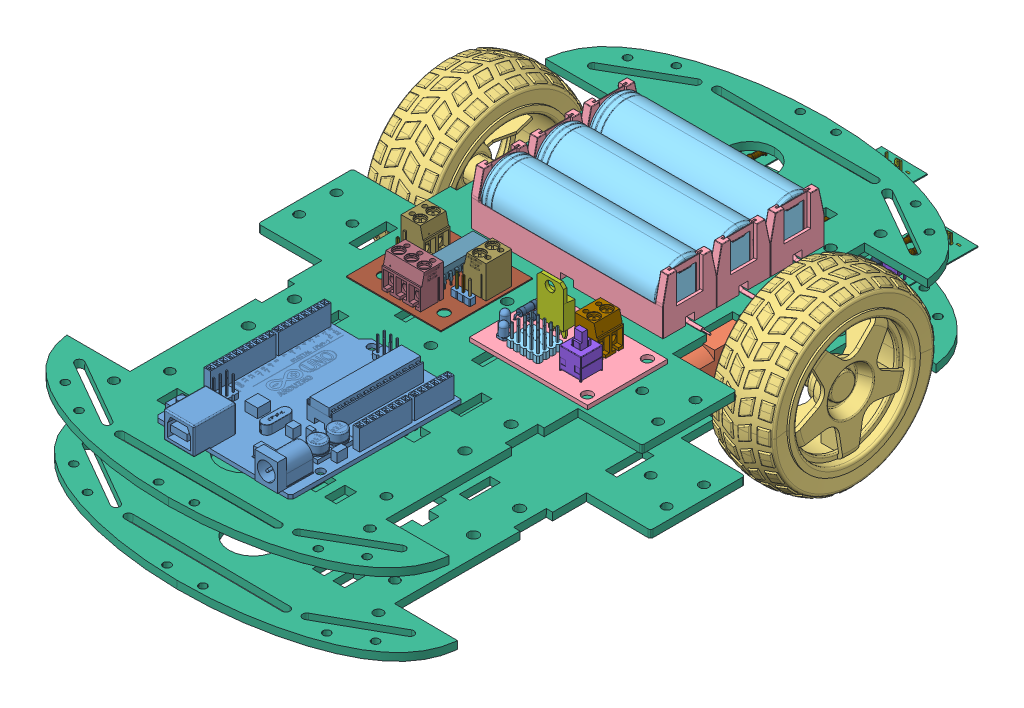
SolidWorks assembly Line Follower, configuration Default. Lengths in mm.
Overall size (160.4 73.81 283.83).
134 component instances, 42 part files, 13 mates.
Components (placement in the parent):
- Arduino-1: Arduino [Predeterminado] at (-169.344 67.8396 211.6674) x (0.008727 0 -0.999962) z (0.999962 0 0.008727) size (74.8 15.1 53.3)
- Motor and Wheel-3: Motor and Wheel [Default] at (-166.8076 90.6853 68.1678) x (1 0 0) z (0 0 -1) size (57.95 69.08 87.78)
  - Motor-1: Motor [Default] at (43.2822 36.5956 -6.1414) size (37.2 22.5 65.5)
  - Wheel-1: Wheel [Default] at (82.6322 37.3457 -18.4581) x (0 0 -1) z (1 0 0) size (69.1 69.08 30)
- Caster Ball Wheel.STEP-1: Caster Ball Wheel.STEP [Default] at (-164.1119 39.4018 172.6288) x (-0.999962 0.008727 0) z (0 0 1) size (47 18.41 32)
  - Wheel''s Body.STEP-1: Wheel''s Body.STEP [Default] at origin size (47 8.6 32)
  - Ball.STEP-1: Ball.STEP [Default] at (0 8.6 0) x (0.870425 -0.365315 -0.330008) z (0.347375 -0.019238 0.937529) size (14 14 14)
- IR Sensor.step-1: IR Sensor.step [Default] at (-98.685 42.2424 150.0634) x (0.008726 -0.000076 -0.999962) z (0.008727 0.999962 0) size (50.17 18.03 34.75)
  - Board.step-1: Board.step [Default] at origin size (50.17 18.03 0.41)
    - Open CASCADE STEP translator 6.8 1.1.1.step-1: Open CASCADE STEP translator 6.8 1.1.1.step [Default] at (0 0 -0.4115) size (50.17 18.03 0.41)
  - TCRT5000.step-1: TCRT5000.step [Default] at origin size (6.8 10.2 11)
    - TCRT5000-0.step-1: TCRT5000-0.step [Default] at (156.0539 65.342 0.0711) x (0 1 0) z (-1 0 0) size (10.2 11 6.8)
  - R4.step-1: R4.step [Default] at origin size (6.55 6.79 6.95)
    - CA6XV5-5KA2020SNP.step-1: CA6XV5-5KA2020SNP.step [Default] at (136.425 60.4731 2.2572) x (-1 0 0) z (0 0 1) size (6.55 6.79 6.95)
  - LM358P.step-1: LM358P.step [Default] at origin size (10.92 9.59 8.26)
    - LM358.step-1: LM358.step [Default] at (125.8569 64.1349 2) x (0 1 0) z (1 0 0) size (9.59 8.26 10.92)
  - LED1.step-1: LED1.step [Default] at origin size (3.57 3.9 31.7)
    - 154003xxx.step-1: 154003xxx.step [Default] at (136.5249 71.3739 0.03) x (-1 0 0) z (0 0 1) size (3.57 3.9 31.7)
  - Free-Models.step-1: Free-Models.step [Default] at origin size (28.98 13.71 11.68)
    - 1x3_TH_Vert_100mil.step-1: 1x3_TH_Vert_100mil.step [Default] at (128.397 72.263 0) x (-1 0 0) z (0 0 1) size (0.64 0.64 3.3)
    - 1x3_TH_Vert_100mil-1.step-1: 1x3_TH_Vert_100mil-1.step [Default] at (128.397 72.263 0) x (-1 0 0) z (0 0 1) size (0.64 0.64 8.38)
    - 1x3_TH_Vert_100mil-2.step-1: 1x3_TH_Vert_100mil-2.step [Default] at (128.397 72.263 0) x (-1 0 0) z (0 0 1) size (0.64 0.64 3.3)
    - 1x3_TH_Vert_100mil-3.step-1: 1x3_TH_Vert_100mil-3.step [Default] at (128.397 72.263 0) x (-1 0 0) z (0 0 1) size (0.64 0.64 8.38)
    - 1x3_TH_Vert_100mil-4.step-1: 1x3_TH_Vert_100mil-4.step [Default] at (128.397 72.263 0) x (-1 0 0) z (0 0 1) size (7.62 2.54 2.5)
    - 1x3_TH_Vert_100mil-5.step-1: 1x3_TH_Vert_100mil-5.step [Default] at (128.397 72.263 0) x (-1 0 0) z (0 0 1) size (0.64 0.64 3.3)
    - 1x3_TH_Vert_100mil-6.step-1: 1x3_TH_Vert_100mil-6.step [Default] at (128.397 72.263 0) x (-1 0 0) z (0 0 1) size (0.64 0.64 8.38)
    - Resistor_10K_Ohm_tol1pct_0,25W__07,62.step-1: Resistor_10K_Ohm_tol1pct_0,25W__07,62.step [Default] at (146.939 71.374 2) x (0 1 0) z (0 0 1) size (2.35 8.17 5.67)
    - Resistor_10K_Ohm_tol1pct_0,25W__07,62.step-2: Resistor_10K_Ohm_tol1pct_0,25W__07,62.step [Default] at (146.939 61 2) x (0 1 0) z (0 0 1) size (2.35 8.17 5.67)
    - Resistor_10K_Ohm_tol1pct_0,25W__07,62.step-3: Resistor_10K_Ohm_tol1pct_0,25W__07,62.step [Default] at (146.939 66.187 2) x (0 -1 0) z (0 0 1) size (2.35 8.17 5.67)
- Power Distribution.step-1: Power Distribution.step [Default] at (-125.3146 67.8396 131.7909) x (-1 0 0) z (0 1 0) size (46.1 31.17 28.88)
  - PCB Component.step-1: PCB Component.step [Default] at origin size (46.1 31.17 28.88)
    - LED3MM.step-1: LED3MM.step [Default] at (30.48 20.32 1.57) x (0 1 0) z (0 0 1) size (3.45 3.85 8.38)
      - LEDBody.step-1: LEDBody.step [Default] at (0 0 0.01) size (3.45 3.85 5.38)
      - Lead1Body.step-1: Lead1Body.step [Default] at (0 0 0.01) size (0.5 0.5 3)
      - Lead2Body.step-1: Lead2Body.step [Default] at (0 0 0.01) size (0.5 0.5 3)
    - LED3MM.step-2: LED3MM.step [Default] at (34.29 16.002 1.57) x (0 1 0) z (0 0 1) size (3.45 3.85 8.38)
      - LEDBody.step-1: LEDBody.step [Default] at (0 0 0.01) size (3.45 3.85 5.38)
      - Lead1Body.step-1: Lead1Body.step [Default] at (0 0 0.01) size (0.5 0.5 3)
      - Lead2Body.step-1: Lead2Body.step [Default] at (0 0 0.01) size (0.5 0.5 3)
    - Board.step-1: Board.step [Default] at origin size (46.1 31.17 1.57)
    - 2X05.step-1: 2X05.step [Default] at (20.828 20.32 1.57) size (12.7 5.08 11.34)
    - 2X05.step-2: 2X05.step [Default] at (20.828 15.24 1.57) x (-1 0 0) z (0 0 1) size (12.7 5.08 11.34)
    - 1N4004.step-1: 1N4004.step [Default] at (20.853 1.118 1.57) x (-1 0 0) z (0 0 1) size (10.6 2.5 4.42)
    - 7805.step-1: 7805.step [Default] at (20.853 11.125 1.57) size (10.39 4.6 28.88)
    - PVA2R.step-1: PVA2R.step [Default] at (4.14 16.459 1.57) size (8.5 8.5 17)
    - AK500_2-H.step-1: AK500_2-H.step [Default] at (7.366 5.588 1.57) x (0 -1 0) z (0 0 1) size (10.6 9 17)
    - 220.step-1: 220.step [Default] at (30.48 7.112 1.57) x (0 -1 0) z (0 0 1) size (10.6 2.5 4.42)
    - 220.step-2: 220.step [Default] at (34.29 7.112 1.57) x (0 -1 0) z (0 0 1) size (10.6 2.5 4.42)
- L293D.STEP-1: L293D.STEP [Default] at (-84.8079 68.2511 189.7872) x (0 0 -1) z (0 1 0) size (35.69 36.96 17)
  - Board.step.STEP-1: Board.step.STEP [Default] at origin size (35.69 36.96 0.41)
    - Open CASCADE STEP translator 6.8 2.1.1.step.STEP-1: Open CASCADE STEP translator 6.8 2.1.1.step.STEP [Default] at (0 0 -0.4115) size (35.69 36.96 0.41)
  - MOTOR2-OUT.step.STEP-1: MOTOR2-OUT.step.STEP [Default] at origin size (10.6 9 17)
    - DG300-5.0-02P-12-00AH.step.STEP-1: DG300-5.0-02P-12-00AH.step.STEP [Default] at (47.6021 120.9511 0) x (1 0 0) z (0 -1 0) size (10.6 17 9)
  - POWER.step.STEP-1: POWER.step.STEP [Default] at origin size (9 15.6 17)
    - DG300-5.0-03P-12-00AH.step.STEP-1: DG300-5.0-03P-12-00AH.step.STEP [Default] at (40.0521 111.8229 0) x (0 -1 0) z (-1 0 0) size (15.6 17 9)
  - MOTOR1-OUT.step.STEP-1: MOTOR1-OUT.step.STEP [Default] at origin size (10.6 9 17)
    - DG300-5.0-02P-12-00AH.step.STEP-1: DG300-5.0-02P-12-00AH.step.STEP [Default] at (57.5539 87.7099 0) x (-1 0 0) z (0 1 0) size (10.6 17 9)
  - L1.step.STEP-1: L1.step.STEP [Default] at origin size (20 9.24 8.4)
    - L293D.step.STEP-1: L293D.step.STEP [Default] at (52.5271 104.2671 1.27) x (1 0 0) z (0 -1 0) size (20 8.4 9.24)
  - Free-Models.step.STEP-1: Free-Models.step.STEP [Default] at origin size (2.54 30.74 11.68)
    - 1x3_TH_Vert_100mil.step.STEP-1: 1x3_TH_Vert_100mil.step.STEP [Default] at (43.688 90.17 0) x (0 1 0) z (0 0 1) size (0.64 0.64 3.3)
    - 1x3_TH_Vert_100mil-0.step.STEP-1: 1x3_TH_Vert_100mil-0.step.STEP [Default] at (43.688 90.17 0) x (0 1 0) z (0 0 1) size (0.64 0.64 8.38)
    - 1x3_TH_Vert_100mil-1.step.STEP-1: 1x3_TH_Vert_100mil-1.step.STEP [Default] at (43.688 90.17 0) x (0 1 0) z (0 0 1) size (0.64 0.64 3.3)
    - 1x3_TH_Vert_100mil-2.step.STEP-1: 1x3_TH_Vert_100mil-2.step.STEP [Default] at (43.688 90.17 0) x (0 1 0) z (0 0 1) size (0.64 0.64 8.38)
    - 1x3_TH_Vert_100mil-3.step.STEP-1: 1x3_TH_Vert_100mil-3.step.STEP [Default] at (43.688 90.17 0) x (0 1 0) z (0 0 1) size (7.62 2.54 2.5)
    - 1x3_TH_Vert_100mil-4.step.STEP-1: 1x3_TH_Vert_100mil-4.step.STEP [Default] at (43.688 90.17 0) x (0 1 0) z (0 0 1) size (0.64 0.64 3.3)
    - 1x3_TH_Vert_100mil-5.step.STEP-1: 1x3_TH_Vert_100mil-5.step.STEP [Default] at (43.688 90.17 0) x (0 1 0) z (0 0 1) size (0.64 0.64 8.38)
    - 1x3_TH_Vert_100mil.step.STEP-2: 1x3_TH_Vert_100mil.step.STEP [Default] at (43.688 113.286 0) x (0 1 0) z (0 0 1) size (0.64 0.64 3.3)
    - 1x3_TH_Vert_100mil-0.step.STEP-2: 1x3_TH_Vert_100mil-0.step.STEP [Default] at (43.688 113.286 0) x (0 1 0) z (0 0 1) size (0.64 0.64 8.38)
    - 1x3_TH_Vert_100mil-1.step.STEP-2: 1x3_TH_Vert_100mil-1.step.STEP [Default] at (43.688 113.286 0) x (0 1 0) z (0 0 1) size (0.64 0.64 3.3)
    - 1x3_TH_Vert_100mil-2.step.STEP-2: 1x3_TH_Vert_100mil-2.step.STEP [Default] at (43.688 113.286 0) x (0 1 0) z (0 0 1) size (0.64 0.64 8.38)
    - 1x3_TH_Vert_100mil-3.step.STEP-2: 1x3_TH_Vert_100mil-3.step.STEP [Default] at (43.688 113.286 0) x (0 1 0) z (0 0 1) size (7.62 2.54 2.5)
    - 1x3_TH_Vert_100mil-4.step.STEP-2: 1x3_TH_Vert_100mil-4.step.STEP [Default] at (43.688 113.286 0) x (0 1 0) z (0 0 1) size (0.64 0.64 3.3)
    - 1x3_TH_Vert_100mil-5.step.STEP-2: 1x3_TH_Vert_100mil-5.step.STEP [Default] at (43.688 113.286 0) x (0 1 0) z (0 0 1) size (0.64 0.64 8.38)
- Motor and Wheel-4: Motor and Wheel [Default] at (-161.9627 17.0365 68.1678) x (-0.999962 0.008727 0) z (0 0 -1) size (57.95 69.08 87.78)
  - Motor-1: Motor [Default] at (43.2822 36.5956 -6.1414) size (37.2 22.5 65.5)
  - Wheel-1: Wheel [Default] at (82.6322 37.3457 -18.4581) x (0 0 -1) z (1 0 0) size (69.1 69.08 30)
- IR Sensor.step-2: IR Sensor.step [Default] at (-64.5985 41.9449 164.3348) x (0.008726 -0.000076 -0.999962) z (0.008727 0.999962 0) size (50.17 18.03 34.75)
  - Board.step-1: Board.step [Default] at origin size (50.17 18.03 0.41)
    - Open CASCADE STEP translator 6.8 1.1.1.step-1: Open CASCADE STEP translator 6.8 1.1.1.step [Default] at (0 0 -0.4115) size (50.17 18.03 0.41)
  - TCRT5000.step-1: TCRT5000.step [Default] at origin size (6.8 10.2 11)
    - TCRT5000-0.step-1: TCRT5000-0.step [Default] at (156.0539 65.342 0.0711) x (0 1 0) z (-1 0 0) size (10.2 11 6.8)
  - R4.step-1: R4.step [Default] at origin size (6.55 6.79 6.95)
    - CA6XV5-5KA2020SNP.step-1: CA6XV5-5KA2020SNP.step [Default] at (136.425 60.4731 2.2572) x (-1 0 0) z (0 0 1) size (6.55 6.79 6.95)
  - LM358P.step-1: LM358P.step [Default] at origin size (10.92 9.59 8.26)
    - LM358.step-1: LM358.step [Default] at (125.8569 64.1349 2) x (0 1 0) z (1 0 0) size (9.59 8.26 10.92)
  - LED1.step-1: LED1.step [Default] at origin size (3.57 3.9 31.7)
    - 154003xxx.step-1: 154003xxx.step [Default] at (136.5249 71.3739 0.03) x (-1 0 0) z (0 0 1) size (3.57 3.9 31.7)
  - Free-Models.step-1: Free-Models.step [Default] at origin size (28.98 13.71 11.68)
    - 1x3_TH_Vert_100mil.step-1: 1x3_TH_Vert_100mil.step [Default] at (128.397 72.263 0) x (-1 0 0) z (0 0 1) size (0.64 0.64 3.3)
    - 1x3_TH_Vert_100mil-1.step-1: 1x3_TH_Vert_100mil-1.step [Default] at (128.397 72.263 0) x (-1 0 0) z (0 0 1) size (0.64 0.64 8.38)
    - 1x3_TH_Vert_100mil-2.step-1: 1x3_TH_Vert_100mil-2.step [Default] at (128.397 72.263 0) x (-1 0 0) z (0 0 1) size (0.64 0.64 3.3)
    - 1x3_TH_Vert_100mil-3.step-1: 1x3_TH_Vert_100mil-3.step [Default] at (128.397 72.263 0) x (-1 0 0) z (0 0 1) size (0.64 0.64 8.38)
    - 1x3_TH_Vert_100mil-4.step-1: 1x3_TH_Vert_100mil-4.step [Default] at (128.397 72.263 0) x (-1 0 0) z (0 0 1) size (7.62 2.54 2.5)
    - 1x3_TH_Vert_100mil-5.step-1: 1x3_TH_Vert_100mil-5.step [Default] at (128.397 72.263 0) x (-1 0 0) z (0 0 1) size (0.64 0.64 3.3)
    - 1x3_TH_Vert_100mil-6.step-1: 1x3_TH_Vert_100mil-6.step [Default] at (128.397 72.263 0) x (-1 0 0) z (0 0 1) size (0.64 0.64 8.38)
    - Resistor_10K_Ohm_tol1pct_0,25W__07,62.step-1: Resistor_10K_Ohm_tol1pct_0,25W__07,62.step [Default] at (146.939 71.374 2) x (0 1 0) z (0 0 1) size (2.35 8.17 5.67)
    - Resistor_10K_Ohm_tol1pct_0,25W__07,62.step-2: Resistor_10K_Ohm_tol1pct_0,25W__07,62.step [Default] at (146.939 61 2) x (0 1 0) z (0 0 1) size (2.35 8.17 5.67)
    - Resistor_10K_Ohm_tol1pct_0,25W__07,62.step-3: Resistor_10K_Ohm_tol1pct_0,25W__07,62.step [Default] at (146.939 66.187 2) x (0 -1 0) z (0 0 1) size (2.35 8.17 5.67)
- IR Sensor.step-3: IR Sensor.step [Default] at (-132.7531 42.5397 164.3348) x (0.008726 -0.000076 -0.999962) z (0.008727 0.999962 0) size (50.17 18.03 34.75)
  - Board.step-1: Board.step [Default] at origin size (50.17 18.03 0.41)
    - Open CASCADE STEP translator 6.8 1.1.1.step-1: Open CASCADE STEP translator 6.8 1.1.1.step [Default] at (0 0 -0.4115) size (50.17 18.03 0.41)
  - TCRT5000.step-1: TCRT5000.step [Default] at origin size (6.8 10.2 11)
    - TCRT5000-0.step-1: TCRT5000-0.step [Default] at (156.0539 65.342 0.0711) x (0 1 0) z (-1 0 0) size (10.2 11 6.8)
  - R4.step-1: R4.step [Default] at origin size (6.55 6.79 6.95)
    - CA6XV5-5KA2020SNP.step-1: CA6XV5-5KA2020SNP.step [Default] at (136.425 60.4731 2.2572) x (-1 0 0) z (0 0 1) size (6.55 6.79 6.95)
  - LM358P.step-1: LM358P.step [Default] at origin size (10.92 9.59 8.26)
    - LM358.step-1: LM358.step [Default] at (125.8569 64.1349 2) x (0 1 0) z (1 0 0) size (9.59 8.26 10.92)
  - LED1.step-1: LED1.step [Default] at origin size (3.57 3.9 31.7)
    - 154003xxx.step-1: 154003xxx.step [Default] at (136.5249 71.3739 0.03) x (-1 0 0) z (0 0 1) size (3.57 3.9 31.7)
  - Free-Models.step-1: Free-Models.step [Default] at origin size (28.98 13.71 11.68)
    - 1x3_TH_Vert_100mil.step-1: 1x3_TH_Vert_100mil.step [Default] at (128.397 72.263 0) x (-1 0 0) z (0 0 1) size (0.64 0.64 3.3)
    - 1x3_TH_Vert_100mil-1.step-1: 1x3_TH_Vert_100mil-1.step [Default] at (128.397 72.263 0) x (-1 0 0) z (0 0 1) size (0.64 0.64 8.38)
    - 1x3_TH_Vert_100mil-2.step-1: 1x3_TH_Vert_100mil-2.step [Default] at (128.397 72.263 0) x (-1 0 0) z (0 0 1) size (0.64 0.64 3.3)
    - 1x3_TH_Vert_100mil-3.step-1: 1x3_TH_Vert_100mil-3.step [Default] at (128.397 72.263 0) x (-1 0 0) z (0 0 1) size (0.64 0.64 8.38)
    - 1x3_TH_Vert_100mil-4.step-1: 1x3_TH_Vert_100mil-4.step [Default] at (128.397 72.263 0) x (-1 0 0) z (0 0 1) size (7.62 2.54 2.5)
    - 1x3_TH_Vert_100mil-5.step-1: 1x3_TH_Vert_100mil-5.step [Default] at (128.397 72.263 0) x (-1 0 0) z (0 0 1) size (0.64 0.64 3.3)
    - 1x3_TH_Vert_100mil-6.step-1: 1x3_TH_Vert_100mil-6.step [Default] at (128.397 72.263 0) x (-1 0 0) z (0 0 1) size (0.64 0.64 8.38)
    - Resistor_10K_Ohm_tol1pct_0,25W__07,62.step-1: Resistor_10K_Ohm_tol1pct_0,25W__07,62.step [Default] at (146.939 71.374 2) x (0 1 0) z (0 0 1) size (2.35 8.17 5.67)
    - Resistor_10K_Ohm_tol1pct_0,25W__07,62.step-2: Resistor_10K_Ohm_tol1pct_0,25W__07,62.step [Default] at (146.939 61 2) x (0 1 0) z (0 0 1) size (2.35 8.17 5.67)
    - Resistor_10K_Ohm_tol1pct_0,25W__07,62.step-3: Resistor_10K_Ohm_tol1pct_0,25W__07,62.step [Default] at (146.939 66.187 2) x (0 -1 0) z (0 0 1) size (2.35 8.17 5.67)
- Power-1: Power [Default] at (-170.9418 66.3043 57.265) x (0 0 -1) z (0 1 0) size (21.01 91 23.5)
  - Battery Holder.stp-1: Battery Holder.stp [Default] at (-10.3221 -7.8579 1.0354) size (21.01 91 22.5)
  - Battery-1: Battery [Default] at (-10.3221 -43.3579 12.5354) size (21 70.03 21)
- Power-2: Power [Default] at (-170.9418 66.3043 78.265) x (0 0 -1) z (0 1 0) size (21.01 91 23.5)
  - Battery Holder.stp-1: Battery Holder.stp [Default] at (-10.3221 -7.8579 1.0354) size (21.01 91 22.5)
  - Battery-1: Battery [Default] at (-10.3221 -43.3579 12.5354) size (21 70.03 21)
- Power-3: Power [Default] at (-170.9418 66.3043 99.265) x (0 0 -1) z (0 1 0) size (21.01 91 23.5)
  - Battery Holder.stp-1: Battery Holder.stp [Default] at (-10.3221 -7.8579 1.0354) size (21.01 91 22.5)
  - Battery-1: Battery [Default] at (-10.3221 -43.3579 12.5354) size (21 70.03 21)
- 4WD Chassis.STEP-1: 4WD Chassis.STEP [Default] at (22.7736 40.771 142.6885) x (0.999962 -0.008727 0) z (-0.008727 -0.999962 0) size (150 257 3)
  - buggy chassis orig v3.stp.STEP-1: buggy chassis orig v3.stp.STEP [Default] at origin size (150 257 3)
- 4WD Chassis.STEP-2: 4WD Chassis.STEP [Default] at (18.4703 67.8396 141.7068) x (1 0 0) z (0 -1 0) size (150 257 3)
  - buggy chassis orig v3.stp.STEP-1: buggy chassis orig v3.stp.STEP [Default] at origin size (150 257 3)
Mates (geometry in assembly coordinates):
- Parallel3: parallel aligned: plane of Motor and Wheel-3/Motor-1 through (-123.5254 54.0896 74.3092) normal (0 0 -1); plane of Motor and Wheel-4/Motor-1 through (-204.9239 54.0085 74.3092) normal (0 0 -1)
- Coincident22: coincident anti-aligned: plane of Power-1/Battery Holder.stp-1 through (-163.0838 67.3396 78.087) normal (0 0 1); plane of Power-2/Battery Holder.stp-1 through (-163.0838 67.3396 78.087) normal (0 0 -1)
- Coincident24: coincident aligned: plane of Power-1/Battery Holder.stp-1 through (-200.5838 67.3396 67.587) normal (-1 0 0); plane of Power-2/Battery Holder.stp-1 through (-200.5838 67.3396 88.587) normal (-1 0 0)
- Coincident25: coincident anti-aligned: plane of Power-2/Battery Holder.stp-1 through (-163.0838 67.3396 99.087) normal (0 0 1); plane of Power-3/Battery Holder.stp-1 through (-163.0838 67.3396 99.087) normal (0 0 -1)
- Coincident26: coincident aligned: plane of Power-2/Battery Holder.stp-1 through (-125.5838 67.3396 88.587) normal (1 0 0); plane of Power-3/Battery Holder.stp-1 through (-125.5838 67.3396 109.587) normal (1 0 0)
- Coincident27: coincident anti-aligned: plane of Motor and Wheel-4/Motor-1 through (-214.3718 42.8405 74.3092) normal (-0.008727 -0.999962 0); plane of 4WD Chassis.STEP-1/buggy chassis orig v3.stp.STEP-1 through (-201.8722 42.7314 206.9385) normal (0.008727 0.999962 0)
- Coincident31: coincident anti-aligned: line of Motor and Wheel-4/Motor-1 through (-214.3718 42.8405 77.7092) axis (0 0 1); line of 4WD Chassis.STEP-1/buggy chassis orig v3.stp.STEP-1 through (-214.3718 42.8405 98.2416) axis (0 0 -1)
- Coincident34: coincident anti-aligned: plane of IR Sensor.step-2/Board.step-1/Open CASCADE STEP translator 6.8 1.1.1.step-1 through (-121.2794 42.0281 51.9489) normal (-0.008727 -0.999962 0); plane of 4WD Chassis.STEP-1/buggy chassis orig v3.stp.STEP-1 through (-201.8722 42.7314 206.9385) normal (0.008727 0.999962 0)
- Coincident35: coincident anti-aligned: plane of IR Sensor.step-1/Board.step-1/Open CASCADE STEP translator 6.8 1.1.1.step-1 through (-155.3659 42.3256 37.6775) normal (-0.008727 -0.999962 0); plane of 4WD Chassis.STEP-1/buggy chassis orig v3.stp.STEP-1 through (-201.8722 42.7314 206.9385) normal (0.008727 0.999962 0)
- Coincident36: coincident anti-aligned: plane of IR Sensor.step-3/Board.step-1/Open CASCADE STEP translator 6.8 1.1.1.step-1 through (-189.4339 42.6229 51.9489) normal (-0.008727 -0.999962 0); plane of 4WD Chassis.STEP-1/buggy chassis orig v3.stp.STEP-1 through (-201.8722 42.7314 206.9385) normal (0.008727 0.999962 0)
- Coincident37: coincident anti-aligned: plane of Caster Ball Wheel.STEP-1/Wheel''s Body.STEP-1 through (-164.1119 39.4018 172.6288) normal (0.008727 0.999962 0); plane of 4WD Chassis.STEP-1/buggy chassis orig v3.stp.STEP-1 through (-201.8984 39.7315 206.9385) normal (-0.008727 -0.999962 0)
- Coincident38: coincident anti-aligned: plane of Power-1/Battery Holder.stp-1 through (-163.0838 67.8396 67.587) normal (0 -1 0); plane of 4WD Chassis.STEP-2/buggy chassis orig v3.stp.STEP-1 through (-206.1842 43.4921 205.9568) normal (0 1 0)
- Parallel7: parallel aligned: plane of 4WD Chassis.STEP-1/buggy chassis orig v3.stp.STEP-1 through (-214.3718 42.8405 161.1515) normal (0 0 1); plane of 4WD Chassis.STEP-2/buggy chassis orig v3.stp.STEP-1 through (-218.6842 67.8396 160.1698) normal (0 0 1)
